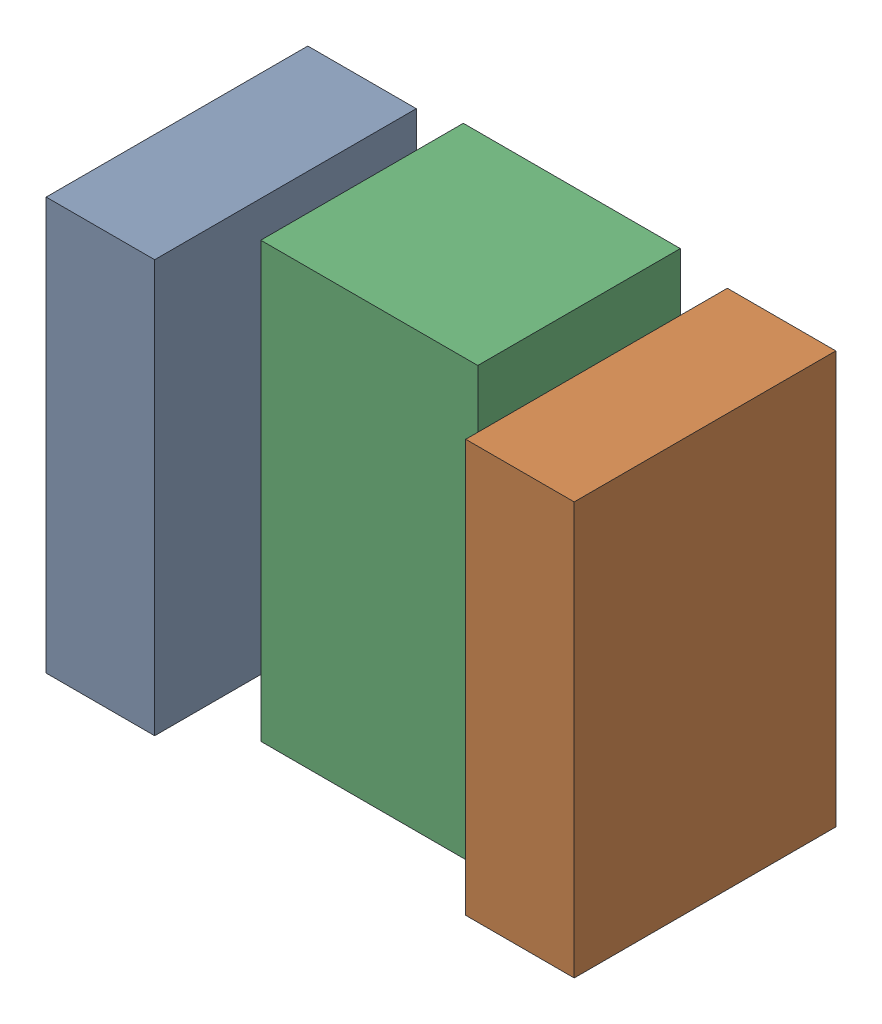
SolidWorks assembly C7_Motor_11Kanaloa_v2.0.0_Motor, configuration Default. Lengths in mm.
Overall size (3.65 3 1.81).
6 component instances, 2 part files, 0 mates.
Components (placement in the parent):
- 334788400-1: 334788400 [Default] at (144.87 167.386 0) size (0.75 2.85 1.81)
  - Extruded_5-1: Extruded_5 [Default] at origin size (0.75 2.85 1.81)
- 334788400-2: 334788400 [Default] at (147.77 167.386 0) size (0.75 2.85 1.81)
  - Extruded_5-1: Extruded_5 [Default] at origin size (0.75 2.85 1.81)
- 334788656-1: 334788656 [Default] at (146.32 167.386 0) size (1.5 3 1.4)
  - Extruded_1-1: Extruded_1 [Default] at origin size (1.5 3 1.4)
